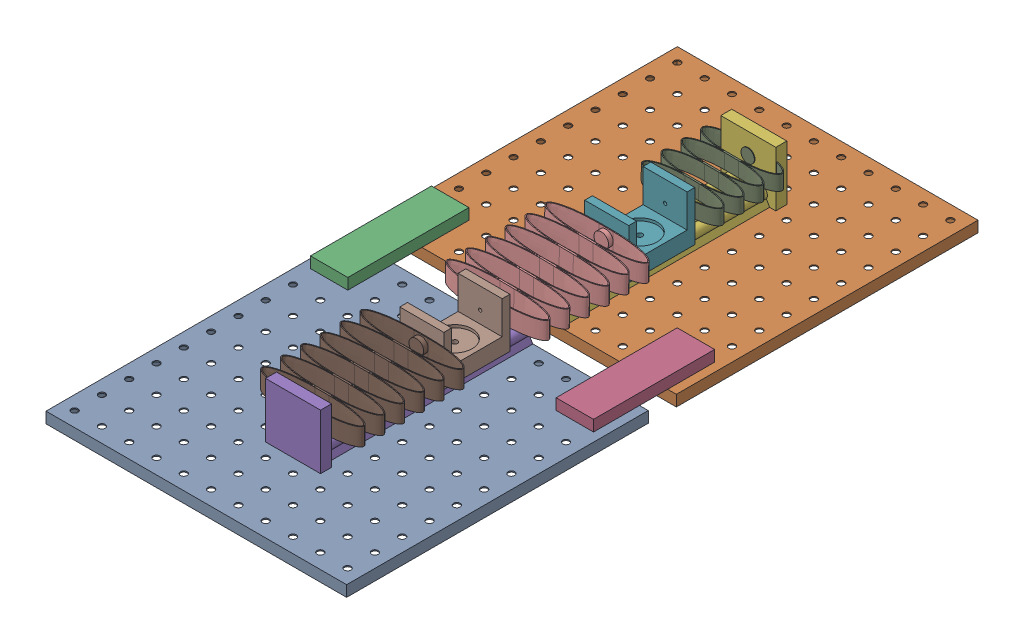
SolidWorks assembly Trans Rail Assembly, configuration Default. Lengths in mm.
Overall size (273.07 60.2 573.53).
11 component instances, 6 part files, 27 mates.
Components (placement in the parent):
- Peg_Board-1: Peg_Board [Default] at (6.2988 67.5311 159.843) size (273.07 10 274)
- Peg_Board-2: Peg_Board [Default] at (6.2988 67.5311 -139.6918) size (273.07 10 274)
- Peg_Board_Spacer-1: Peg_Board_Spacer [Default] at (-117.7018 77.5311 -40.9552) size (34 10 110)
- Peg_Board_Spacer-3: Peg_Board_Spacer [Default] at (105.4982 77.5311 -40.9552) size (34 10 110)
- Linear_Rail_A-1: Linear_Rail_A [Default] at (6.2982 85.7272 12.1796) size (50 50 198.4)
- Linear_Rail_A-2: Linear_Rail_A [Default] at (31.0982 85.7272 7.0448) x (-1 0 0) z (0 0 -1) size (50 50 198.4)
- Cart-1: Cart [Default] at (19.6132 82.7272 -81.3793) x (0 0 -1) z (0 1 0) size (60 40 45)
- Cart-2: Cart [Default] at (19.6132 82.7272 86.6207) x (0 0 -1) z (0 1 0) size (60 40 45)
- Modular_Magnetic_Spring 4-1: Modular_Magnetic_Spring 4 [Default] at (18.6982 108.7272 -186.6015) x (0.999992 -0.003875 0) z (0 0 1) size (72.7 13.5 72)
- Modular_Magnetic_Spring 3-1: Modular_Magnetic_Spring 3 [Default] at (18.6982 108.7272 -54.6015) x (0.999958 -0.009153 0) z (0 0 1) size (92.7 16 108)
- Modular_Magnetic_Spring 3-2: Modular_Magnetic_Spring 3 [Default] at (18.6982 108.7272 113.3985) size (92.7 16 108)
Mates (geometry in assembly coordinates):
- Parallel1: parallel anti-aligned: plane of Peg_Board-1 through (-130.2368 77.5311 22.8446) normal (0 0 -1); plane of Peg_Board-2 through (-130.2368 77.5311 -2.6934) normal (0 0 1)
- Coincident2: coincident aligned: plane of Peg_Board-1 through (142.8345 77.5311 296.8414) normal (1 0 0); plane of Peg_Board-2 through (142.8345 77.5311 -2.6934) normal (1 0 0)
- Coincident3: coincident aligned: plane of Peg_Board-1 through (6.2988 77.5311 159.843) normal (0 1 0); plane of Peg_Board-2 through (6.2988 77.5311 -139.6918) normal (0 1 0)
- Coincident4: coincident anti-aligned: plane of Peg_Board-1 through (6.2988 77.5311 159.843) normal (0 1 0); plane of Peg_Board_Spacer-1 through (-117.7018 77.5311 -40.9552) normal (0 -1 0)
- Concentric4: concentric anti-aligned: circle of Peg_Board-1; circle of Peg_Board_Spacer-1
- Concentric5: concentric aligned: circle of Peg_Board-2; circle of Peg_Board_Spacer-1
- Coincident5: coincident anti-aligned: plane of Peg_Board-1 through (6.2988 77.5311 159.843) normal (0 1 0); plane of Peg_Board_Spacer-3 through (105.4982 77.5311 -40.9552) normal (0 -1 0)
- Concentric6: concentric anti-aligned: circle of Peg_Board-1; circle of Peg_Board_Spacer-3
- Concentric7: concentric aligned: circle of Peg_Board-2; circle of Peg_Board_Spacer-3
- Concentric9: concentric anti-aligned: circle of Peg_Board-1; circle of Linear_Rail_A-1
- Coincident7: coincident anti-aligned: plane of Peg_Board-1 through (6.2988 77.5311 159.843) normal (0 1 0); plane of Linear_Rail_A-1 through (6.2982 77.5311 232.1796) normal (0 -1 0)
- Concentric10: concentric anti-aligned: circle of Peg_Board-1; circle of Linear_Rail_A-1
- Coincident8: coincident anti-aligned: plane of Peg_Board-2 through (6.2988 77.5311 -139.6918) normal (0 1 0); plane of Linear_Rail_A-2 through (31.0982 77.5311 -212.9552) normal (0 -1 0)
- Concentric11: concentric anti-aligned: circle of Peg_Board-2; circle of Linear_Rail_A-2
- Concentric12: concentric anti-aligned: circle of Peg_Board-2; circle of Linear_Rail_A-2
- Concentric13: concentric anti-aligned: cylinder of Linear_Rail_A-2 through (6.2982 85.7272 -212.9552) axis (0 0 1) radius 5; cylinder of Cart-1 through (6.2982 85.7272 -60.6015) axis (0 0 -1) radius 5.2
- Concentric14: concentric anti-aligned: cylinder of Linear_Rail_A-2 through (31.0982 85.7272 -212.9552) axis (0 0 1) radius 5; cylinder of Cart-1 through (31.0982 85.7272 -60.6015) axis (0 0 -1) radius 5.2
- Concentric15: concentric aligned: cylinder of Linear_Rail_A-1 through (6.2982 85.7272 232.1796) axis (0 0 -1) radius 5; cylinder of Cart-2 through (6.2982 85.7272 107.3985) axis (0 0 -1) radius 5.2
- Concentric16: concentric aligned: cylinder of Linear_Rail_A-1 through (31.0982 85.7272 232.1796) axis (0 0 -1) radius 5; cylinder of Cart-2 through (31.0982 85.7272 107.3985) axis (0 0 -1) radius 5.2
- Concentric17: concentric aligned: circle of Cart-1; circle of Modular_Magnetic_Spring 4-1
- Coincident9: coincident anti-aligned: plane of Cart-1 through (-1.3018 97.7272 -123.6015) normal (0 0 -1); plane of Modular_Magnetic_Spring 4-1 through (12.3744 115.5018 -123.6015) normal (0 0 1)
- Coincident12: coincident anti-aligned: plane of Cart-1 through (-1.3018 97.7272 -63.6015) normal (0 0 1); plane of Modular_Magnetic_Spring 3-1 through (12.4217 116.785 -63.6015) normal (0 0 -1)
- Concentric18: concentric aligned: circle of Cart-1; circle of Modular_Magnetic_Spring 3-1
- Concentric20: concentric aligned: circle of Cart-2; circle of Modular_Magnetic_Spring 3-1
- Coincident13: coincident anti-aligned: plane of Cart-2 through (-1.3018 97.7272 44.3985) normal (0 0 -1); plane of Modular_Magnetic_Spring 3-1 through (12.4217 116.785 44.3985) normal (0 0 1)
- Coincident14: coincident anti-aligned: plane of Cart-2 through (-1.3018 97.7272 104.3985) normal (0 0 1); plane of Modular_Magnetic_Spring 3-2 through (12.3482 116.7272 104.3985) normal (0 0 -1)
- Concentric21: concentric aligned: circle of Cart-2; circle of Modular_Magnetic_Spring 3-2
